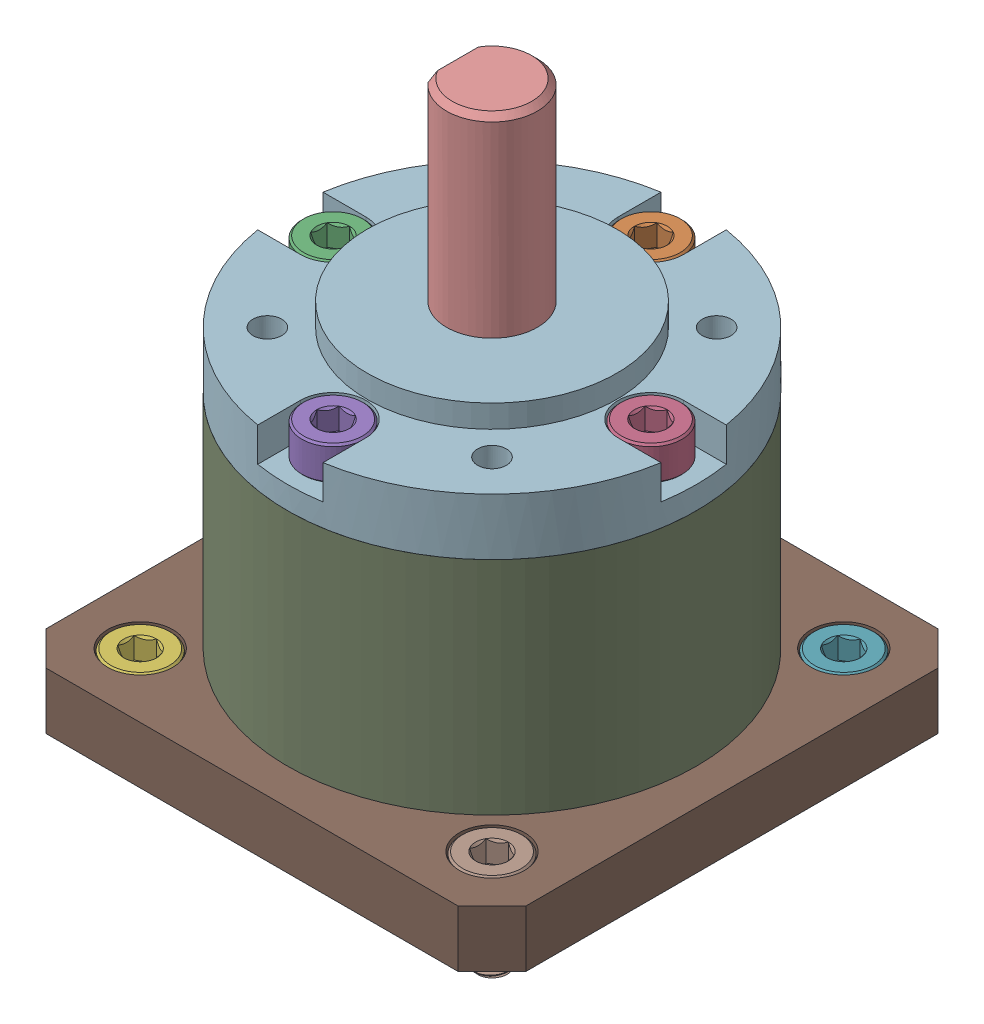
SolidWorks assembly Nema 17 5_1 Planetary Gearbox.step, configuration Default. Lengths in mm.
Overall size (42.3 52.5 42.3).
13 component instances, 5 part files, 0 mates.
Components (placement in the parent):
- Screws.step-1: Screws.step [Default] at origin size (36.5 33.5 36.5)
  - M3 x 6mm.step-1: M3 x 6mm.step [Default] at (-15.5 44 -15.5) x (1 0 0) z (0 -1 0) size (5.5 5.5 9)
  - M3 x 6mm.step-2: M3 x 6mm.step [Default] at (0 68.5 -14) x (0 0 1) z (0 -1 0) size (5.5 5.5 9)
  - M3 x 6mm.step-3: M3 x 6mm.step [Default] at (-14 68.5 0) x (1 0 0) z (0 -1 0) size (5.5 5.5 9)
  - M3 x 6mm.step-4: M3 x 6mm.step [Default] at (14 68.5 0) x (-1 0 0) z (0 -1 0) size (5.5 5.5 9)
  - M3 x 6mm.step-5: M3 x 6mm.step [Default] at (0 68.5 14) x (0 0 -1) z (0 -1 0) size (5.5 5.5 9)
  - M3 x 6mm.step-6: M3 x 6mm.step [Default] at (-15.5 44 15.5) x (1 0 0) z (0 -1 0) size (5.5 5.5 9)
  - M3 x 6mm.step-7: M3 x 6mm.step [Default] at (15.5 44 -15.5) x (1 0 0) z (0 -1 0) size (5.5 5.5 9)
  - M3 x 6mm.step-8: M3 x 6mm.step [Default] at (15.5 44 15.5) x (1 0 0) z (0 -1 0) size (5.5 5.5 9)
- Mid_1.step-1: Mid_1.step [Default] at origin size (36 19.5 36)
- Shaft_1.step-1: Shaft_1.step [Default] at origin size (8 19 8)
- Nema 17 5_1 Planetary Gearbox-4.step-1: Nema 17 5_1 Planetary Gearbox-4.step [Default] at origin size (42.3 5 42.3)
- Nema 17 5_1 Planetary Gearbox-5.step-1: Nema 17 5_1 Planetary Gearbox-5.step [Default] at origin size (36 7 36)
